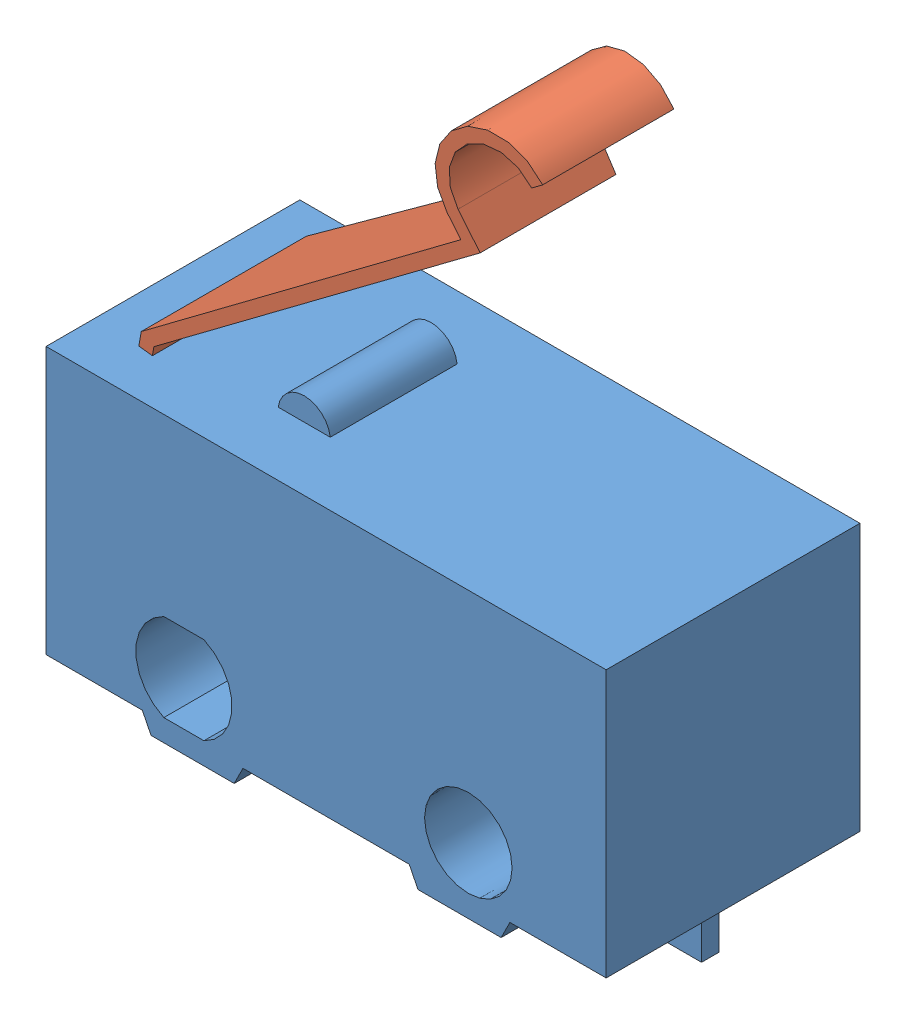
SolidWorks assembly D2F_L3_D, configuration Default. Lengths in mm.
Overall size (12.8 16.51 5.8).
2 component instances, 2 part files, 0 mates.
Components (placement in the parent):
- D2F_01FL3_BASE-1: D2F_01FL3_BASE [Default] at origin size (12.8 7.92 5.8)
- D2F_L3_D_ACTUATOR-1: D2F_L3_D_ACTUATOR [Default] at (-8.25 5 0) x (0.984836 -0.173489 0) z (0 0 1) size (7.42 9.2 3.77)
